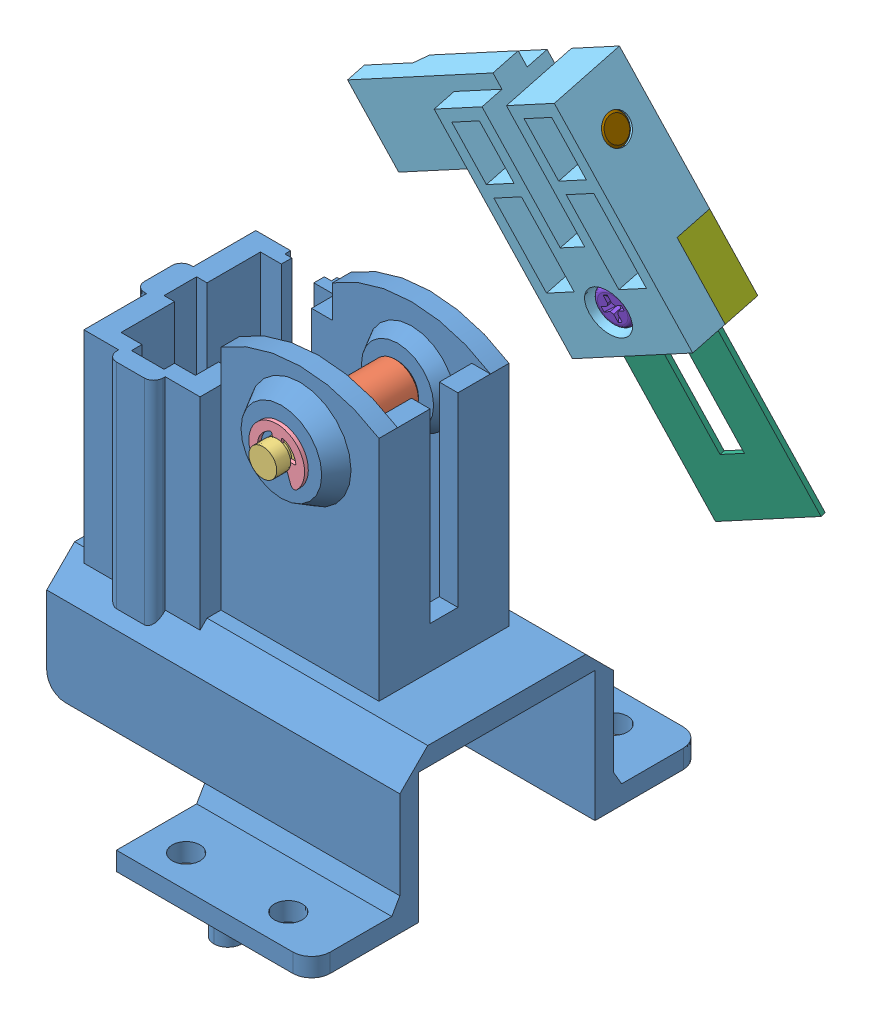
SolidWorks assembly TP n°2 - 2eme Partie, configuration éclaté. Lengths in mm.
Overall size (49.2 49.73 65.34).
12 component instances, 9 part files, 0 mates.
Components (placement in the parent):
- ensemble Guide coulisseau-1: ensemble Guide coulisseau [Défaut] x (0 0 -1) z (1 0 0) size (42 45.5 38)
  - Guide coulisseau-1: Guide coulisseau [Défaut] at origin size (42 45.5 38)
  - entroise axe levier-1: entroise axe levier [Défaut] x (0 0 -1) z (1 0 0) size (5 5 7)
  - axe levier-1: axe levier [Défaut] x (0 0 -1) z (1 0 0) size (3 3 22)
  - anneau truac d3-1: anneau truac d3 [Défaut] at (9.1 35.8667 14.75) size (0.4 5.2 6)
  - anneau truac d3-2: anneau truac d3 [Défaut] at (-9.5 35.8667 14.75) size (0.4 5.2 6)
- coulisseau-1: coulisseau [Défaut] at (1.2181 37.4685 -34.1774) x (-0.08048 0.157017 -0.984311) z (0.878526 0.477674 0.004367) size (7.75 42 26.8)
  - coulisseau1-1: coulisseau1 [Défaut] at origin size (7.75 24.5 26.8)
  - poincon-1: poincon [Défaut] x (0 0 -1) z (1 0 0) size (13 25.5 0.5)
  - coulisseau2-1: coulisseau2 [Défaut] x (0 0 -1) z (1 0 0) size (14.8 9 3.88)
  - Vis M2,5 (L5)-1: Vis M2,5 (L5) [Défaut] at (-1.875 -14 0) x (0 0 1) z (-1 0 0) size (4 4 6.5)
  - axe coulisseau-1: axe coulisseau [Défaut] at origin size (3 3 14.8)
